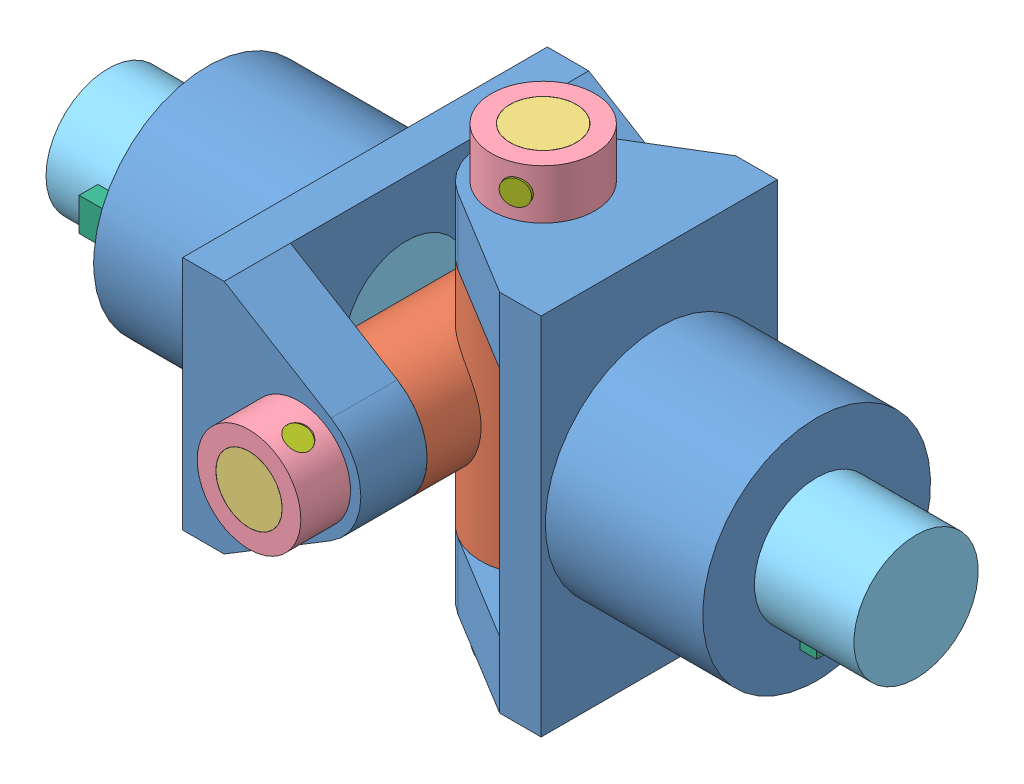
SolidWorks assembly Assem1, configuration Default. Lengths in mm.
Overall size (195 110 110).
13 component instances, 7 part files, 33 mates.
Components (placement in the parent):
- Part1-1: Part1 [Default] at (44.4604 59.2026 39.009) x (1 0 0) z (0 0 1) size (81 57 88)
- Part2-1: Part2 [Default] at (44.4604 59.2026 67.009) x (0 -1 0) z (-1 0 0) size (56 56 45)
- Part3-1: Part3 [Default] at (44.4604 59.2026 13.009) x (0.87861 -0.477539 0) z (-0.477539 -0.87861 0) size (25 110 25)
- Part4-1: Part4 [Default] at (44.4604 59.2026 123.009) x (0.477539 0.87861 0) z (-0.87861 0.477539 0) size (25 12 25)
- Part5-1: Part5 [Default] at (6.4604 59.2026 67.009) x (0 -1 0) z (0 0 -1) size (30 72 30)
- Part6-1: Part6 [Default] at (-33.5396 59.2026 82.009) x (0 1 0) z (0 0 -1) size (8 40 8)
- Part7-1: Part7 [Default] at (38.3167 47.8989 117.009) x (0.87861 -0.477539 0) z (0 0 1) size (6 25 6)
- Part1-2: Part1 [Default] at (59.4604 87.2026 67.009) x (-1 0 0) z (0 -1 0) size (81 57 88)
- Part3-2: Part3 [Default] at (59.4604 5.2026 67.009) x (0.917861 0 -0.396901) z (0.396901 0 0.917861) size (25 110 25)
- Part4-2: Part4 [Default] at (59.4604 115.2026 67.009) x (-0.396901 0 -0.917861) z (-0.917861 0 0.396901) size (25 12 25)
- Part7-2: Part7 [Default] at (54.6441 109.2026 55.8711) x (0.791384 -0.506561 -0.34221) z (-0.464953 -0.862204 0.201055) size (6 25 6)
- Part5-2: Part5 [Default] at (129.4604 59.2026 67.009) x (0 0 -1) z (0 1 0) size (30 72 30)
- Part6-2: Part6 [Default] at (89.4604 44.2026 67.009) x (0 0 1) z (0 1 0) size (8 40 8)
Mates (geometry in assembly coordinates):
- Concentric1: concentric anti-aligned: cylinder of Part1-1 through (44.4604 59.2026 95.009) axis (0 0 1) radius 8; cylinder of Part2-1 through (44.4604 59.2026 95.009) axis (0 0 -1) radius 8
- Coincident1: coincident anti-aligned: plane of Part1-1 through (44.4604 59.2026 95.009) normal (0 0 -1); plane of Part2-1 through (44.4604 59.2026 95.009) normal (0 0 1)
- Concentric2: concentric anti-aligned: cylinder of Part1-1 through (44.4604 59.2026 95.009) axis (0 0 1) radius 8; cylinder of Part3-1 through (44.4604 59.2026 123.009) axis (0 0 -1) radius 8
- Coincident2: coincident anti-aligned: plane of Part1-1 through (44.4604 59.2026 23.009) normal (0 0 -1); plane of Part3-1 through (44.4604 59.2026 23.009) normal (0 0 1)
- Concentric3: concentric anti-aligned: cylinder of Part3-1 through (44.4604 59.2026 123.009) axis (0 0 -1) radius 8; cylinder of Part4-1 through (44.4604 59.2026 111.009) axis (0 0 1) radius 8
- Concentric4: concentric anti-aligned: cylinder of Part3-1 through (68.3374 103.1331 117.009) axis (-0.477539 -0.87861 0) radius 3; cylinder of Part4-1 through (32.9994 38.1159 117.009) axis (0.477539 0.87861 0) radius 3
- Parallel1: parallel aligned: plane of Part5-1 through (-33.5396 63.2026 78.009) normal (0 0 1); plane of Part6-1 through (6.4604 55.2026 86.009) normal (0 0 1)
- Coincident4: coincident: line of Part5-1 through (-33.5396 55.2026 81.4658) axis (1 0 0); plane of Part6-1 through (6.4604 55.2026 86.009) normal (0 -1 0)
- Coincident5: coincident anti-aligned: plane of Part5-1 through (-33.5396 59.2026 67.009) normal (1 0 0); plane of Part6-1 through (-33.5396 59.2026 82.009) normal (-1 0 0)
- Coincident6: coincident anti-aligned: plane of Part5-1 through (-33.5396 63.2026 78.009) normal (0 0 1); plane of Part6-1 through (6.4604 55.2026 78.009) normal (0 0 -1)
- Concentric5: concentric aligned: cylinder of Part1-1 through (-21.5396 59.2026 67.009) axis (1 0 0) radius 15; cylinder of Part5-1 through (-33.5396 59.2026 67.009) axis (1 0 0) radius 15
- Coincident7: coincident anti-aligned: plane of Part1-1 through (-21.5396 63.2026 86.009) normal (0 0 -1); plane of Part6-1 through (6.4604 55.2026 86.009) normal (0 0 1)
- Concentric6: concentric: cylinder of Part4-1 through (19.0013 27.7305 130.8977) axis (0.360192 0.932878 0) radius 3; cylinder of ? through (46.4463 98.8118 130.8977) axis (0.360192 0.932878 0) radius 3
- Concentric7: concentric aligned: cylinder of Part4-1 through (16.1849 29.033 130.8977) axis (0.477539 0.87861 0) radius 3; cylinder of ? through (39.627 72.1634 130.8977) axis (0.477539 0.87861 0) radius 3
- Concentric8: concentric anti-aligned: cylinder of Part4-1 through (32.9994 38.1159 117.009) axis (0.477539 0.87861 0) radius 3; cylinder of Part7-1 through (50.2552 69.8642 117.009) axis (-0.477539 -0.87861 0) radius 3
- Tangent1: tangent: curve of Part4-1; circle of Part7-1
- Concentric10: concentric anti-aligned: cylinder of Part2-1 through (59.4604 31.2026 67.009) axis (0 1 0) radius 8; cylinder of Part1-2 through (59.4604 31.2026 67.009) axis (0 -1 0) radius 8
- Coincident9: coincident anti-aligned: plane of Part2-1 through (59.4604 31.2026 67.009) normal (0 -1 0); plane of Part1-2 through (59.4604 31.2026 67.009) normal (0 1 0)
- Concentric11: concentric anti-aligned: cylinder of Part2-1 through (59.4604 31.2026 67.009) axis (0 1 0) radius 8; cylinder of Part3-2 through (59.4604 115.2026 67.009) axis (0 -1 0) radius 8
- Coincident10: coincident anti-aligned: plane of Part1-2 through (77.4604 15.2026 38.509) normal (0 -1 0); plane of Part3-2 through (59.4604 15.2026 67.009) normal (0 1 0)
- Concentric12: concentric anti-aligned: cylinder of Part3-2 through (59.4604 115.2026 67.009) axis (0 -1 0) radius 8; cylinder of Part4-2 through (59.4604 103.2026 67.009) axis (0 1 0) radius 8
- Concentric13: concentric anti-aligned: cylinder of Part3-2 through (39.6153 109.2026 21.1159) axis (0.396901 0 0.917861) radius 3; cylinder of Part4-2 through (68.986 109.2026 89.0377) axis (-0.396901 0 -0.917861) radius 3
- Concentric14: concentric aligned: cylinder of Part4-2 through (68.986 109.2026 89.0377) axis (-0.396901 0 -0.917861) radius 3; cylinder of Part7-2 through (64.5667 109.2026 78.8176) axis (-0.396901 0 -0.917861) radius 3
- Tangent2: tangent: curve of Part4-2; circle of Part7-2
- Coincident11: coincident: line of Part5-2 through (89.4604 44.7457 71.009) axis (1 0 0); plane of Part6-2 through (129.4604 40.2026 71.009) normal (0 0 1)
- Coincident12: coincident anti-aligned: plane of Part5-2 through (129.4604 59.2026 67.009) normal (-1 0 0); plane of Part6-2 through (129.4604 44.2026 67.009) normal (1 0 0)
- Coincident14: coincident anti-aligned: plane of Part5-2 through (89.4604 48.2026 71.009) normal (0 -1 0); plane of Part6-2 through (129.4604 48.2026 63.009) normal (0 1 0)
- Coincident15: coincident anti-aligned: plane of Part1-2 through (125.4604 40.2026 63.009) normal (0 1 0); plane of Part6-2 through (129.4604 40.2026 63.009) normal (0 -1 0)
- Concentric15: concentric anti-aligned: cylinder of Part1-2 through (125.4604 59.2026 67.009) axis (-1 0 0) radius 15; cylinder of Part5-2 through (89.4604 59.2026 67.009) axis (1 0 0) radius 15
- Coincident16: coincident aligned: plane of Part1-2 through (77.4604 87.2026 67.009) normal (-1 0 0); plane of Part5-2 through (77.4604 59.2026 67.009) normal (-1 0 0)
- Coincident17: coincident aligned: plane of Part1-1 through (26.4604 59.2026 39.009) normal (1 0 0); plane of Part5-1 through (26.4604 59.2026 67.009) normal (1 0 0)
- Parallel2: parallel anti-aligned: plane of Part1-1 through (44.4604 59.2026 39.009) normal (0 0 1); plane of Part1-2
- Parallel3: parallel anti-aligned: plane of Part1-1 through (44.4604 59.2026 39.009) normal (0 1 0); plane of Part1-2 through (59.4604 87.2026 67.009) normal (0 -1 0)
